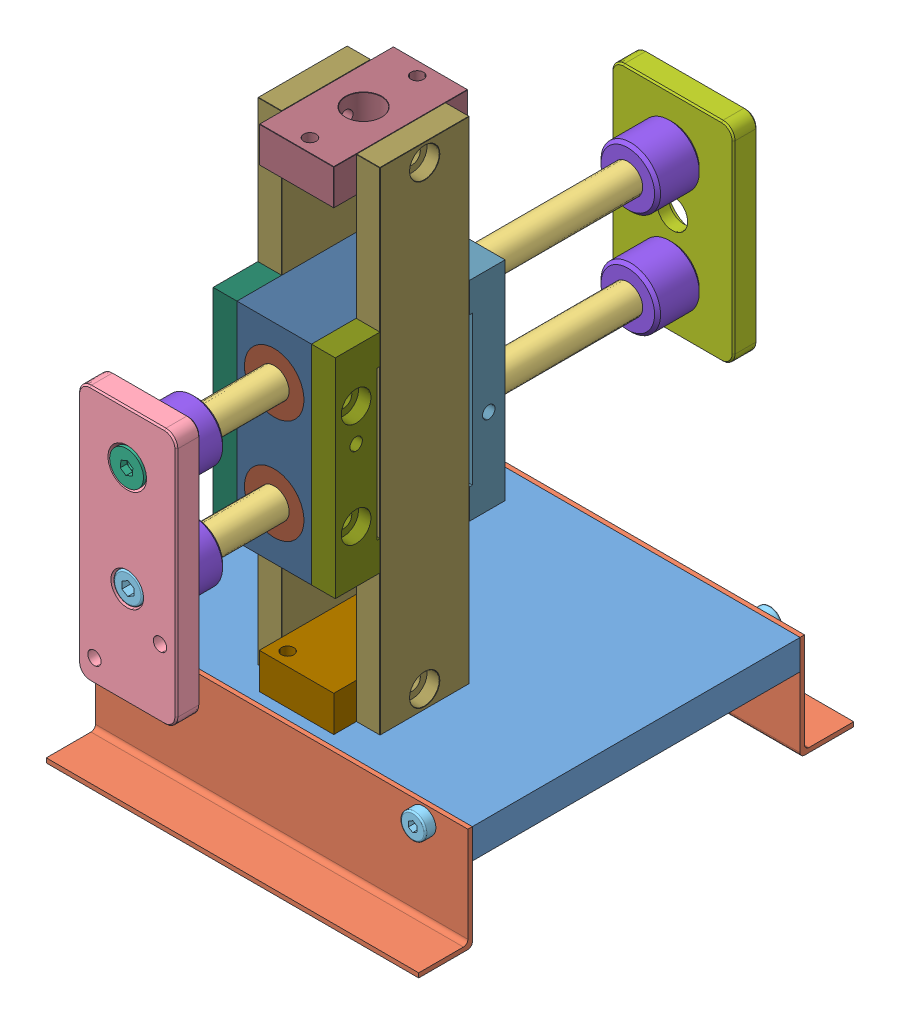
SolidWorks assembly cum_s4, configuration Default. Lengths in mm.
Overall size (125 200 191.44).
34 component instances, 16 part files, 75 mates.
Components (placement in the parent):
- tam_de-1: tam_de [Default] at (55.7373 162.4347 98.3877) size (125 10 110)
- khoi_do-1: khoi_do [Default] at (118.2373 137.4347 153.3877) x (0 0 1) z (0 -1 0) size (18 125 35)
- khoi_do-2: khoi_do [Default] at (-6.7627 137.4347 43.3877) x (0 0 -1) z (0 -1 0) size (18 125 35)
- chot_dan_huong-1: chot_dan_huong [Default] at (55.7373 272.187 198.7148) x (0.807467 -0.589913 0) z (0.589913 0.807467 0) size (10 175 10)
- chot_dan_huong-2: chot_dan_huong [Default] at (55.7373 237.187 198.7148) x (0.458763 0.888559 0) z (-0.888559 0.458763 0) size (10 175 10)
- ban_canh_truoc-1: ban_canh_truoc [Default] at (55.7373 246.687 198.7148) x (1 0 0) z (0 -1 0) size (33 8 86)
- socket head thin cap screw_din-14: socket head thin cap screw_din [DIN 7984 - M5 x 8 --- 5.6N] at (8.2373 167.4347 38.3877) x (0 0 1) z (-1 0 0) size (11.5 8.5 8.5)
- socket head thin cap screw_din-16: socket head thin cap screw_din [DIN 7984 - M5 x 8 --- 5.6N] at (8.2373 167.4347 158.3877) x (0 0 -1) z (1 0 0) size (11.5 8.5 8.5)
- socket head thin cap screw_din-17: socket head thin cap screw_din [DIN 7984 - M5 x 8 --- 5.6N] at (103.2373 167.4347 158.3877) x (0 0 -1) z (1 0 0) size (11.5 8.5 8.5)
- socket head thin cap screw_din-18: socket head thin cap screw_din [DIN 7984 - M5 x 8 --- 5.6N] at (63.2373 164.6347 109.3877) x (0 1 0) z (0 0 1) size (11.5 8.5 8.5)
- socket head thin cap screw_din-19: socket head thin cap screw_din [DIN 7984 - M5 x 8 --- 5.6N] at (48.2373 164.6347 145.3877) x (0 1 0) z (0 0 1) size (11.5 8.5 8.5)
- socket head thin cap screw_din-22: socket head thin cap screw_din [DIN 7984 - M5 x 8 --- 5.6N] at (103.2373 167.4347 38.3877) x (0 0 1) z (-1 0 0) size (11.5 8.5 8.5)
- socket head thin cap screw_din-23: socket head thin cap screw_din [DIN 7984 - M6 x 10 --- 7N] at (55.7373 237.187 15.9148) x (0 0 1) z (-1 0 0) size (14 10 10)
- socket head thin cap screw_din-24: socket head thin cap screw_din [DIN 7984 - M6 x 10 --- 7N] at (55.7373 236.9507 206.5148) x (0 0 -1) z (1 0 0) size (14 10 10)
- socket csink head cap screw 10642_din-2: socket csink head cap screw 10642_din [EN ISO 10642 - M6 x 8 - 8N] at (55.7373 272.187 15.4948) x (0 0 1) z (-0.997818 -0.066017 0) size (8 11.34 11.34)
- socket csink head cap screw 10642_din-3: socket csink head cap screw 10642_din [EN ISO 10642 - M6 x 8 - 8N] at (55.7373 272.187 206.9348) x (0 0 -1) z (0.99607 -0.088565 0) size (8 11.34 11.34)
- s3_ban_canh_sau-1: s3_ban_canh_sau [Default] at (55.7373 254.687 23.7148) x (-1 0 0) z (0 -1 0) size (41 8 70)
- bac_chan-1: bac_chan [Default] at (55.7373 272.187 183.7148) x (-0.999622 -0.027501 0) z (-0.027501 0.999622 0) size (20 15 20)
- bac_chan-2: bac_chan [Default] at (55.7373 237.187 183.7148) x (1 0 0) z (0 -1 0) size (20 15 20)
- bac_chan-3: bac_chan [Default] at (55.7373 272.187 38.7148) x (1 0 0) z (0 1 0) size (20 15 20)
- bac_chan-4: bac_chan [Default] at (55.7373 237.187 38.7148) x (1 0 0) z (0 1 0) size (20 15 20)
- mieng_dem_duoi-1: mieng_dem_duoi [Default] at (55.7373 172.4347 127.3877) size (25 12 45)
- con_truot_s4_as-1: con_truot_s4_as [Default] at (19.8229 199.4385 110.8419) x (0 0 1) z (0 1 0) size (45 28.02 70)
  - con_truot_s4-1: con_truot_s4 [Default] at (24.0458 23.4144 55.2485) size (45 25 70)
  - bat_lot-1: bat_lot [Default] at (46.5458 35.9144 72.7485) x (0 0.967524 -0.252781) z (0 0.252781 0.967524) size (20 10 20)
  - bat_lot-2: bat_lot [Default] at (46.5458 35.9144 37.7485) x (0 0.967524 -0.252781) z (0 0.252781 0.967524) size (20 10 20)
  - bat_lot-3: bat_lot [Default] at (1.5458 35.9144 72.7485) x (0 0.603074 -0.797685) z (0 -0.797685 -0.603074) size (20 10 20)
  - bat_lot-4: bat_lot [Default] at (1.5458 35.9144 37.7485) x (0 0.603074 -0.797685) z (0 -0.797685 -0.603074) size (20 10 20)
- thanh_dan_huong_lon-1: thanh_dan_huong_lon [Default] at (68.2373 254.9347 127.3877) x (0 0 -1) z (0 -1 0) size (30 8 165)
- thanh_dan_huong_lon-2: thanh_dan_huong_lon [Default] at (43.2373 254.9347 127.3877) x (0 0 -1) z (0 1 0) size (30 8 165)
- mieng_dem_tren-1: mieng_dem_tren [Default] at (55.7373 325.4347 127.3877) size (25 12 45)
- tam_dan_huong-1: tam_dan_huong [Default] at (35.2373 254.687 106.3877) x (0 0 -1) z (0 -1 0) size (12 41 70)
- thanh_dan_huong_nho_1-1: thanh_dan_huong_nho_1 [Default] at (43.2373 254.687 149.8877) x (0 0 -1) z (0 1 0) size (15 8 70)
- thanh_dan_huong_nho_2-1: thanh_dan_huong_nho_2 [Default] at (68.2373 254.687 149.8877) x (0 0 -1) z (0 -1 0) size (15 8 70)
Mates (geometry in assembly coordinates):
- Parallel1: parallel aligned: plane of tam_de-1 through (-6.7627 172.4347 153.3877) normal (0 0 1); plane of khoi_do-1 through (-6.7627 172.4347 154.8877) normal (0 0 1)
- Concentric1: concentric aligned: cylinder of tam_de-1 through (8.2373 167.4347 153.3877) axis (0 0 1) radius 2.1; circle of khoi_do-1
- Concentric2: concentric aligned: circle of tam_de-1; circle of khoi_do-1
- Coincident1: coincident anti-aligned: plane of tam_de-1 through (-6.7627 172.4347 153.3877) normal (0 0 1); plane of khoi_do-1 through (-6.7627 137.4347 153.3877) normal (0 0 -1)
- Parallel2: parallel anti-aligned: plane of tam_de-1 through (-6.7627 172.4347 43.3877) normal (0 0 -1); plane of khoi_do-2 through (118.2373 137.4347 43.3877) normal (0 0 1)
- Concentric3: concentric aligned: circle of tam_de-1; cylinder of khoi_do-2 through (8.2373 167.4347 43.3877) axis (0 0 -1) radius 2.75
- Parallel3: parallel aligned: plane of tam_de-1 through (55.7373 172.4347 98.3877) normal (0 1 0); plane of khoi_do-2 through (118.2373 172.4347 43.3877) normal (0 1 0)
- Coincident2: coincident anti-aligned: plane of tam_de-1 through (-6.7627 172.4347 43.3877) normal (0 0 -1); plane of khoi_do-2 through (118.2373 137.4347 43.3877) normal (0 0 1)
- Concentric18: concentric aligned: cylinder of chot_dan_huong-2 through (55.7373 237.187 198.7148) axis (0 0 1) radius 2.5; circle of ban_canh_truoc-1
- Concentric19: concentric anti-aligned: circle of chot_dan_huong-1; circle of ban_canh_truoc-1
- Coincident14: coincident aligned: plane of chot_dan_huong-1 through (55.7373 272.187 198.7148) normal (0 0 1); circle of ban_canh_truoc-1
- Coincident15: coincident aligned: circle of chot_dan_huong-2; plane of ban_canh_truoc-1 through (55.7373 246.687 198.7148) normal (0 0 -1)
- Concentric37: concentric aligned: cylinder of khoi_do-2 through (8.2373 167.4347 43.3877) axis (0 0 -1) radius 2.75; cylinder of socket head thin cap screw_din-14 through (8.2373 167.4347 6.6377) axis (0 0 -1) radius 4.25
- Coincident28: coincident anti-aligned: plane of khoi_do-2 through (118.2373 172.4347 41.8877) normal (0 0 -1); plane of socket head thin cap screw_din-14 through (8.2373 171.6847 41.8877) normal (0 0 1)
- Concentric39: concentric aligned: cylinder of khoi_do-1 through (8.2373 167.4347 153.3877) axis (0 0 1) radius 2.75; cylinder of socket head thin cap screw_din-16 through (8.2373 167.4347 190.1377) axis (0 0 1) radius 4.25
- Coincident30: coincident anti-aligned: plane of khoi_do-1 through (-6.7627 172.4347 154.8877) normal (0 0 1); plane of socket head thin cap screw_din-16 through (8.2373 171.6847 154.8877) normal (0 0 -1)
- Concentric40: concentric aligned: cylinder of khoi_do-1 through (103.2373 167.4347 153.3877) axis (0 0 1) radius 2.75; cylinder of socket head thin cap screw_din-17 through (103.2373 167.4347 190.1377) axis (0 0 1) radius 4.25
- Coincident31: coincident anti-aligned: plane of khoi_do-1 through (-6.7627 172.4347 154.8877) normal (0 0 1); plane of socket head thin cap screw_din-17 through (103.2373 171.6847 154.8877) normal (0 0 -1)
- Concentric41: concentric aligned: cylinder of tam_de-1 through (63.2373 172.4347 109.3877) axis (0 -1 0) radius 2.75; cylinder of socket head thin cap screw_din-18 through (63.2373 132.8847 109.3877) axis (0 -1 0) radius 4.25
- Coincident32: coincident anti-aligned: plane of tam_de-1 through (63.2373 168.1347 109.3877) normal (0 -1 0); plane of socket head thin cap screw_din-18 through (58.9873 168.1347 109.3877) normal (0 1 0)
- Concentric42: concentric aligned: cylinder of tam_de-1 through (48.2373 172.4347 145.3877) axis (0 -1 0) radius 2.75; cylinder of socket head thin cap screw_din-19 through (48.2373 132.8847 145.3877) axis (0 -1 0) radius 4.25
- Coincident33: coincident anti-aligned: plane of tam_de-1 through (48.2373 168.1347 145.3877) normal (0 -1 0); plane of socket head thin cap screw_din-19 through (43.9873 168.1347 145.3877) normal (0 1 0)
- Concentric451: concentric aligned: cylinder of khoi_do-2 through (103.2373 167.4347 43.3877) axis (0 0 -1) radius 2.75; cylinder of socket head thin cap screw_din-22 through (103.2373 167.4347 6.6377) axis (0 0 -1) radius 4.25
- Coincident361: coincident anti-aligned: plane of khoi_do-2 through (118.2373 172.4347 41.8877) normal (0 0 -1); plane of socket head thin cap screw_din-22 through (103.2373 171.6847 41.8877) normal (0 0 1)
- Concentric47: concentric aligned: cylinder of ban_canh_truoc-1 through (55.7373 236.9507 202.5148) axis (0 0 1) radius 5.5; cylinder of socket head thin cap screw_din-24 through (55.7373 236.9507 238.2648) axis (0 0 1) radius 5
- Coincident38: coincident anti-aligned: plane of ban_canh_truoc-1 through (55.7373 236.9507 202.5148) normal (0 0 1); plane of socket head thin cap screw_din-24 through (55.7373 241.9507 202.5148) normal (0 0 -1)
- Coincident40: coincident aligned: cone of ban_canh_truoc-1 through (55.7373 272.187 203.5148) axis (0 0 -1); cylinder of socket csink head cap screw 10642_din-3 through (55.7373 272.187 205.8848) axis (0 0 -1) radius 785.3982
- Concentric452: concentric aligned: circle of chot_dan_huong-2; circle of s3_ban_canh_sau-1
- Coincident362: coincident anti-aligned: plane of chot_dan_huong-1 through (55.7373 272.187 23.7148) normal (0 0 -1); plane of s3_ban_canh_sau-1 through (55.7373 254.687 23.7148) normal (0 0 1)
- Concentric453: concentric anti-aligned: cylinder of socket csink head cap screw 10642_din-2 through (55.7373 272.187 15.4948) axis (0 0 -1) radius 3; cylinder of s3_ban_canh_sau-1 through (55.7373 272.187 15.7148) axis (0 0 1) radius 3.3
- Coincident363: coincident aligned: cylinder of socket csink head cap screw 10642_din-2 through (55.7373 272.187 16.5448) axis (0 0 1) radius 785.3982; cylinder of s3_ban_canh_sau-1 through (55.7373 272.187 18.9148) axis (0 0 1) radius 785.3982
- Concentric454: concentric aligned: cylinder of chot_dan_huong-2 through (55.7373 237.187 23.7148) axis (0 0 -1) radius 2.5; cylinder of socket head thin cap screw_din-23 through (55.7373 237.187 -15.8352) axis (0 0 -1) radius 3
- Coincident364: coincident anti-aligned: plane of socket head thin cap screw_din-23 through (55.7373 242.187 19.9148) normal (0 0 1); plane of s3_ban_canh_sau-1 through (55.7373 237.187 19.9148) normal (0 0 -1)
- Concentric456: concentric anti-aligned: cylinder of chot_dan_huong-1 through (55.7373 272.187 23.7148) axis (0 0 1) radius 5; cylinder of bac_chan-1 through (55.7373 272.187 198.7148) axis (0 0 -1) radius 5
- Coincident366: coincident anti-aligned: plane of ban_canh_truoc-1 through (55.7373 246.687 198.7148) normal (0 0 -1); plane of bac_chan-1 through (55.7373 272.187 198.7148) normal (0 0 1)
- Concentric457: concentric anti-aligned: cylinder of chot_dan_huong-2 through (55.7373 237.187 23.7148) axis (0 0 1) radius 5; circle of bac_chan-2
- Coincident367: coincident anti-aligned: plane of ban_canh_truoc-1 through (55.7373 246.687 198.7148) normal (0 0 -1); plane of bac_chan-2 through (55.7373 237.187 198.7148) normal (0 0 1)
- Concentric458: concentric anti-aligned: cylinder of chot_dan_huong-1 through (55.7373 272.187 23.7148) axis (0 0 1) radius 5; circle of bac_chan-3
- Coincident368: coincident anti-aligned: plane of s3_ban_canh_sau-1 through (55.7373 254.687 23.7148) normal (0 0 1); plane of bac_chan-3 through (55.7373 272.187 23.7148) normal (0 0 -1)
- Concentric459: concentric anti-aligned: cylinder of chot_dan_huong-2 through (55.7373 237.187 23.7148) axis (0 0 1) radius 5; circle of bac_chan-4
- Coincident369: coincident anti-aligned: plane of s3_ban_canh_sau-1 through (55.7373 254.687 23.7148) normal (0 0 1); plane of bac_chan-4 through (55.7373 237.187 23.7148) normal (0 0 -1)
- Concentric460: concentric anti-aligned: cylinder of socket head thin cap screw_din-19 through (48.2373 132.8847 145.3877) axis (0 -1 0) radius 2.5; cylinder of mieng_dem_duoi-1 through (48.2373 184.4347 145.3877) axis (0 1 0) radius 2.1
- Concentric461: concentric anti-aligned: cylinder of socket head thin cap screw_din-18 through (63.2373 132.8847 109.3877) axis (0 -1 0) radius 2.5; cylinder of mieng_dem_duoi-1 through (63.2373 184.4347 109.3877) axis (0 1 0) radius 2.1
- Coincident371: coincident anti-aligned: plane of tam_de-1 through (55.7373 172.4347 98.3877) normal (0 1 0); plane of mieng_dem_duoi-1 through (55.7373 172.4347 127.3877) normal (0 -1 0)
- Parallel6: parallel anti-aligned: plane of mieng_dem_duoi-1 through (55.7373 184.4347 127.3877) normal (0 1 0); plane of con_truot_s4_as-1/con_truot_s4-1 through (226.6799 219.687 112.3877) normal (0 -1 0)
- Parallel7: parallel aligned: plane of mieng_dem_duoi-1 through (68.2373 184.4347 149.8877) normal (1 0 0); plane of con_truot_s4_as-1/con_truot_s4-1 through (68.2373 254.687 134.8877) normal (1 0 0)
- Coincident372: coincident aligned: plane of mieng_dem_duoi-1 through (68.2373 184.4347 149.8877) normal (1 0 0); plane of con_truot_s4_as-1/con_truot_s4-1 through (68.2373 254.687 134.8877) normal (1 0 0)
- Concentric464: concentric aligned: cylinder of chot_dan_huong-2 through (55.7373 237.187 23.7148) axis (0 0 1) radius 5; cylinder of con_truot_s4_as-1/bat_lot-2 through (55.7373 237.187 147.3877) axis (0 0 1) radius 5
- Concentric465: concentric aligned: cylinder of chot_dan_huong-1 through (55.7373 272.187 23.7148) axis (0 0 1) radius 5; circle of con_truot_s4_as-1/con_truot_s4-1
- Parallel9: parallel aligned: plane of con_truot_s4_as-1/con_truot_s4-1 through (68.2373 254.687 134.8877) normal (1 0 0); plane of thanh_dan_huong_lon-1 through (76.2373 254.9347 127.3877) normal (1 0 0)
- Concentric466: concentric anti-aligned: circle of mieng_dem_duoi-1; circle of thanh_dan_huong_lon-1
- Parallel10: parallel aligned: plane of con_truot_s4_as-1/con_truot_s4-1 through (68.2373 305.687 112.3877) normal (0 0 -1); plane of thanh_dan_huong_lon-1 through (76.2373 172.4347 112.3877) normal (0 0 -1)
- Coincident374: coincident anti-aligned: plane of mieng_dem_duoi-1 through (68.2373 184.4347 149.8877) normal (1 0 0); plane of thanh_dan_huong_lon-1 through (68.2373 254.9347 127.3877) normal (-1 0 0)
- Parallel11: parallel: line of thanh_dan_huong_lon-1 through (68.2373 337.3347 112.4877) axis (0 -1 0); plane of thanh_dan_huong_lon-2 through (35.2373 337.4347 142.3877) normal (0 0 1)
- Parallel12: parallel aligned: plane of thanh_dan_huong_lon-1 through (68.2373 254.9347 127.3877) normal (-1 0 0); plane of thanh_dan_huong_lon-2 through (35.2373 254.9347 127.3877) normal (-1 0 0)
- Concentric467: concentric anti-aligned: cylinder of mieng_dem_duoi-1 through (68.2373 178.4347 127.3877) axis (1 0 0) radius 2.1; circle of thanh_dan_huong_lon-2
- Coincident375: coincident anti-aligned: plane of mieng_dem_duoi-1 through (43.2373 184.4347 149.8877) normal (-1 0 0); plane of thanh_dan_huong_lon-2 through (43.2373 254.9347 127.3877) normal (1 0 0)
- Concentric468: concentric aligned: cylinder of thanh_dan_huong_lon-2 through (39.4373 331.4347 127.3877) axis (-1 0 0) radius 5; cylinder of mieng_dem_tren-1 through (43.2373 331.4347 127.3877) axis (-1 0 0) radius 2.1
- Parallel13: parallel aligned: plane of mieng_dem_duoi-1 through (55.7373 184.4347 127.3877) normal (0 1 0); plane of mieng_dem_tren-1 through (55.7373 337.4347 127.3877) normal (0 1 0)
- Coincident376: coincident anti-aligned: plane of thanh_dan_huong_lon-2 through (43.2373 254.9347 127.3877) normal (1 0 0); plane of mieng_dem_tren-1 through (43.2373 337.4347 149.8877) normal (-1 0 0)
- Parallel14: parallel anti-aligned: plane of con_truot_s4_as-1/con_truot_s4-1 through (68.2373 305.687 112.3877) normal (0 0 -1); plane of tam_dan_huong-1 through (76.2373 279.687 111.3877) normal (0 0 1)
- Parallel15: parallel anti-aligned: plane of con_truot_s4_as-1/con_truot_s4-1 through (193.5245 289.687 112.3877) normal (0 1 0); plane of tam_dan_huong-1 through (76.2373 219.687 112.3877) normal (0 -1 0)
- Concentric469: concentric aligned: circle of con_truot_s4_as-1/con_truot_s4-1; circle of tam_dan_huong-1
- Coincident377: coincident anti-aligned: plane of con_truot_s4_as-1/con_truot_s4-1 through (68.2373 305.687 112.3877) normal (0 0 -1); plane of tam_dan_huong-1 through (76.2373 279.687 112.3877) normal (0 0 1)
- Concentric470: concentric anti-aligned: circle of con_truot_s4_as-1/con_truot_s4-1; circle of thanh_dan_huong_nho_1-1
- Concentric474: concentric anti-aligned: cylinder of con_truot_s4_as-1/con_truot_s4-1 through (68.2373 237.187 150.3877) axis (1 0 0) radius 2.1; cylinder of thanh_dan_huong_nho_1-1 through (39.4373 237.187 150.3877) axis (-1 0 0) radius 5
- Coincident378: coincident anti-aligned: plane of con_truot_s4_as-1/con_truot_s4-1 through (43.2373 254.687 134.8877) normal (-1 0 0); plane of thanh_dan_huong_nho_1-1 through (43.2373 254.687 149.8877) normal (1 0 0)
- Coincident379: coincident anti-aligned: plane of thanh_dan_huong_lon-2 through (35.2373 337.4347 112.3877) normal (0 0 -1); plane of tam_dan_huong-1 through (76.2373 279.687 112.3877) normal (0 0 1)
- Concentric475: concentric anti-aligned: circle of con_truot_s4_as-1/con_truot_s4-1; circle of thanh_dan_huong_nho_2-1
- Concentric476: concentric anti-aligned: circle of con_truot_s4_as-1/con_truot_s4-1; circle of thanh_dan_huong_nho_2-1
- Coincident380: coincident anti-aligned: plane of con_truot_s4_as-1/con_truot_s4-1 through (68.2373 254.687 134.8877) normal (1 0 0); plane of thanh_dan_huong_nho_2-1 through (68.2373 254.687 149.8877) normal (-1 0 0)
- Coincident381: coincident anti-aligned: plane of s3_ban_canh_sau-1 through (55.7373 254.687 23.7148) normal (0 0 1); plane of bac_chan-3 through (55.7373 272.187 23.7148) normal (0 0 -1)
- Concentric477: concentric aligned: circle of s3_ban_canh_sau-1; circle of bac_chan-3
- LimitDistance2: limit distance = 41.3271 mm anti-aligned: plane of ban_canh_truoc-1 through (55.7373 246.687 198.7148) normal (0 0 -1); plane of con_truot_s4_as-1/con_truot_s4-1 through (68.2373 305.687 157.3877) normal (0 0 1)
- LimitDistance5: limit distance = 35.2523 mm anti-aligned: plane of con_truot_s4_as-1/con_truot_s4-1 through (226.6799 219.687 112.3877) normal (0 -1 0); plane of mieng_dem_duoi-1 through (55.7373 184.4347 127.3877) normal (0 1 0)
